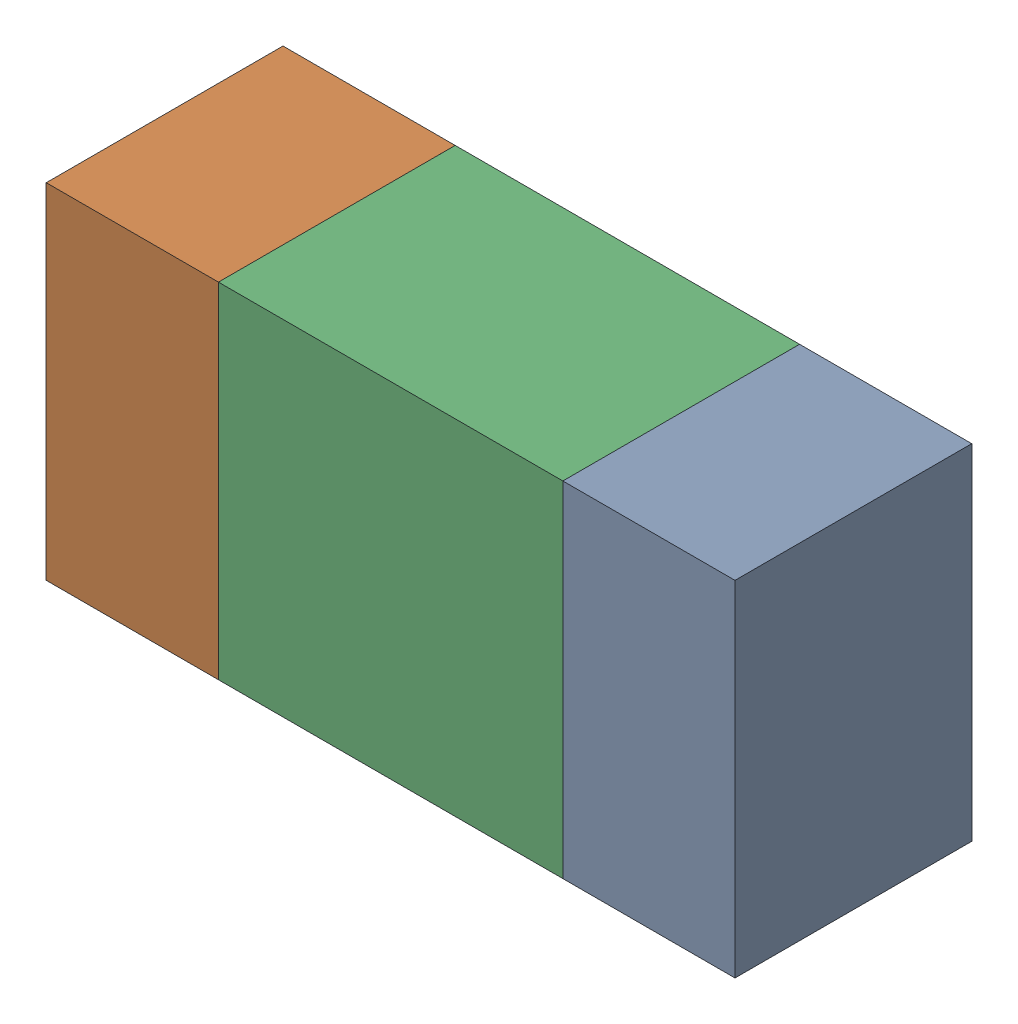
SolidWorks assembly R26, configuration ﾃﾞﾌｫﾙﾄ. Lengths in mm.
Overall size (1.6 0.8 0.55).
6 component instances, 2 part files, 0 mates.
Components (placement in the parent):
- 689261512-1: 689261512 [ﾃﾞﾌｫﾙﾄ] at (60.5999 52.9999 0) size (0.4 0.8 0.55)
  - Extruded_32-1: Extruded_32 [ﾃﾞﾌｫﾙﾄ] at origin size (0.4 0.8 0.55)
- 689261512-2: 689261512 [ﾃﾞﾌｫﾙﾄ] at (59.3999 52.9999 0) size (0.4 0.8 0.55)
  - Extruded_32-1: Extruded_32 [ﾃﾞﾌｫﾙﾄ] at origin size (0.4 0.8 0.55)
- 689261648-1: 689261648 [ﾃﾞﾌｫﾙﾄ] at (60 52.9999 0) size (0.8 0.8 0.55)
  - Extruded_33-1: Extruded_33 [ﾃﾞﾌｫﾙﾄ] at origin size (0.8 0.8 0.55)
